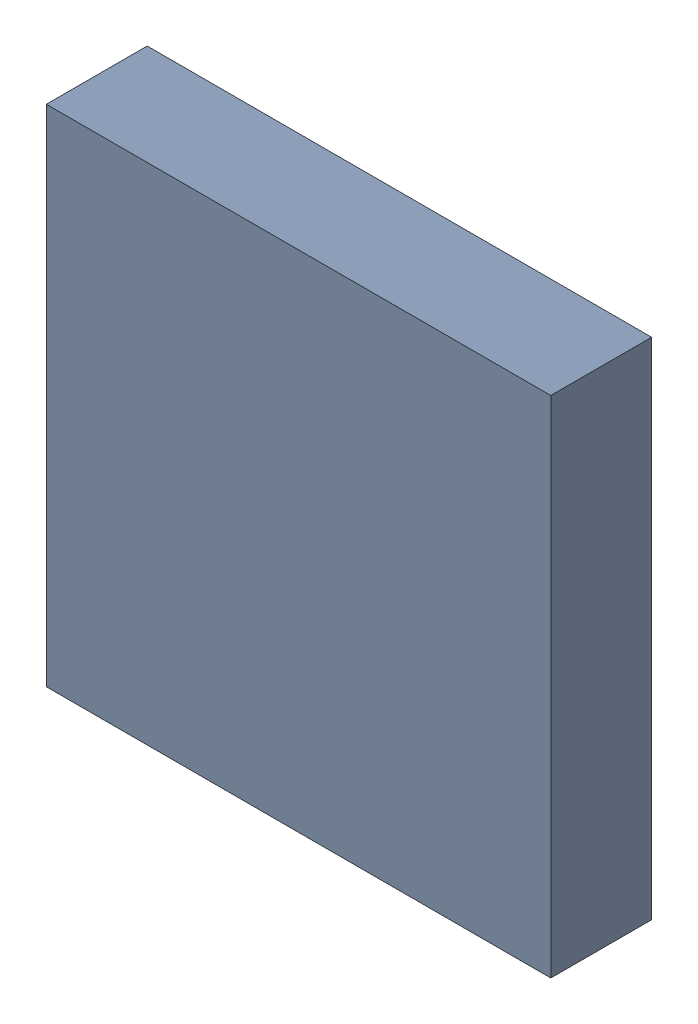
SolidWorks assembly U19, configuration Default. Lengths in mm.
Overall size (4 4 0.8).
2 component instances, 1 part files, 0 mates.
Components (placement in the parent):
- 836758000-1: 836758000 [Default] at (120.4 57.55 0) size (4 4 0.8)
  - Extruded_18-1: Extruded_18 [Default] at origin size (4 4 0.8)
